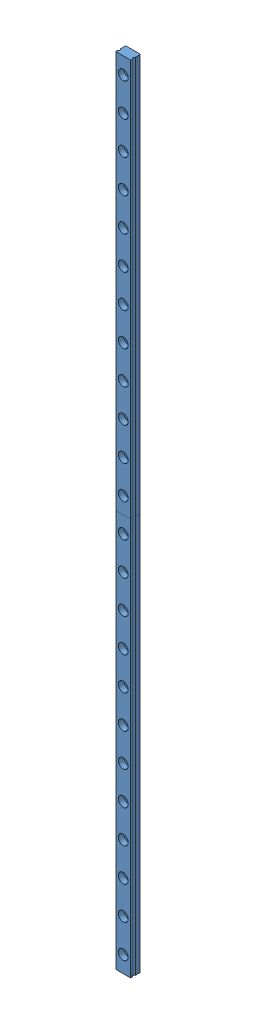
SolidWorks assembly thanh_truot, configuration Default. Lengths in mm.
Overall size (9 480 6).
2 component instances, 1 part files, 3 mates.
Components (placement in the parent):
- IKO LWL9 BCS linear guideway rail 240mm-1: IKO LWL9 BCS linear guideway rail 240mm [Default] at (15.9848 104.6266 13.1828) size (9 240 6)
- IKO LWL9 BCS linear guideway rail 240mm-2: IKO LWL9 BCS linear guideway rail 240mm [Default] at (15.9848 -135.3734 13.1828) size (9 240 6)
Mates (geometry in assembly coordinates):
- Coincident6: coincident anti-aligned: plane of IKO LWL9 BCS linear guideway rail 240mm-1 through (18.2348 -15.3734 16.1828) normal (0 -1 0); plane of IKO LWL9 BCS linear guideway rail 240mm-2 through (18.2348 -15.3734 16.1828) normal (0 1 0)
- Coincident7: coincident aligned: plane of IKO LWL9 BCS linear guideway rail 240mm-1 through (18.2348 -15.3734 19.1828) normal (0 0 1); plane of IKO LWL9 BCS linear guideway rail 240mm-2 through (18.2348 -255.3734 19.1828) normal (0 0 1)
- Coincident8: coincident aligned: plane of IKO LWL9 BCS linear guideway rail 240mm-1 through (11.4848 -15.3734 14.9078) normal (-1 0 0); plane of IKO LWL9 BCS linear guideway rail 240mm-2 through (11.4848 -255.3734 14.9078) normal (-1 0 0)
